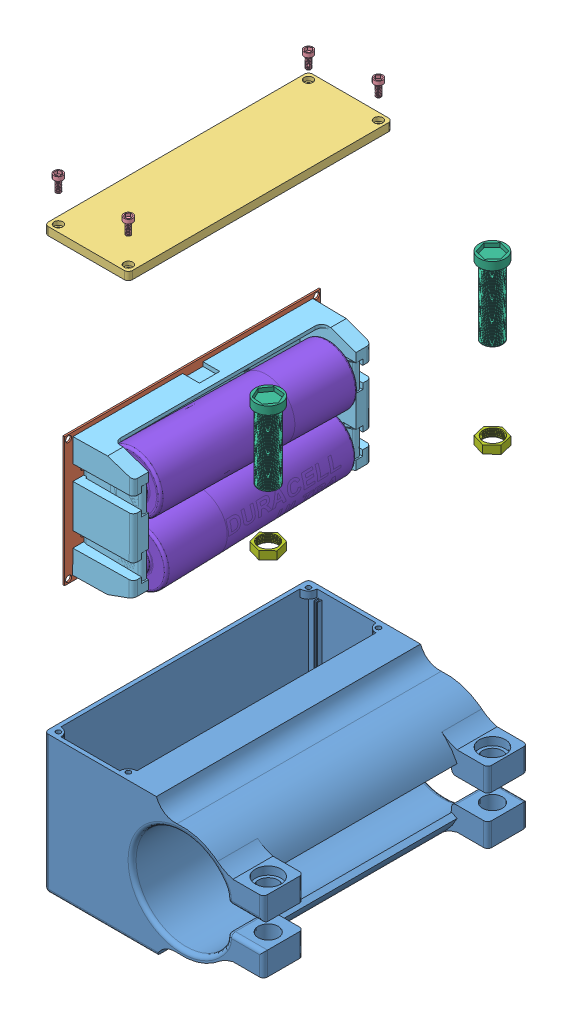
SolidWorks assembly Ensamblaje, configuration Predeterminado. Lengths in mm.
Overall size (55.54 155.38 66.01).
15 component instances, 9 part files, 19 mates.
Components (placement in the parent):
- Pieza_Delantera-1: Pieza_Delantera [Predeterminado] at (-76.9358 49.8795 33.005) size (54.77 34.5 66.01)
- PCB_Dispositivo-1: PCB_Dispositivo [Predeterminado] at (-73.2858 112.174 32.005) x (0 1 0) z (-1 0 0) size (32.26 64.01 2.93)
- Pieza_Tapadera-1: Pieza_Tapadera [Predeterminado] at (-55.9358 193.6998 -33.005) x (0 0 1) z (1 0 0) size (66.01 2 21)
- Pieza_Tornillo_Peque-1: Pieza_Tornillo_Peque [Predeterminado] at (-75.1756 204.7566 31.2449) x (-0.969898 0 -0.243511) z (-0.243511 0 0.969898) size (2.2 4.01 2.2)
- Pieza_Tornillo_Peque-2: Pieza_Tornillo_Peque [Predeterminado] at (-57.6959 204.2798 31.2449) x (0.987486 0 -0.157707) z (-0.157707 0 -0.987486) size (2.2 4.01 2.2)
- Pieza_Tornillo_Peque-3: Pieza_Tornillo_Peque [Predeterminado] at (-57.6959 202.9475 -31.2449) x (-0.365026 0 0.930997) z (0.930997 0 0.365026) size (2.2 4.01 2.2)
- Pieza_Tornillo_Peque-4: Pieza_Tornillo_Peque [Predeterminado] at (-75.1756 200.2508 -31.2449) x (0.24603 0 0.969262) z (0.969262 0 -0.24603) size (2.2 4.01 2.2)
- User Library-1013-1-1: User Library-1013-1 [Default] at (-72.8743 133.2117 -0.0275) x (0 0.001436 0.999999) z (1 0 0) size (60.04 29.98 18.93)
- Pieza_Tubo-1: Pieza_Tubo [Predeterminado] at (-42.499 66.6295 97.4394) x (0.561173 -0.827699 0) z (0.827699 0.561173 0) size (25 200 25) (hidden)
- Pieza_tornillo_grande-1: Pieza_tornillo_grande [Predeterminado] at (-25.9904 182.887 -28.005) x (0.687028 0 0.726631) z (0.726631 0 -0.687028) size (6.5 19.01 6.5)
- Pieza_tornillo_grande-2: Pieza_tornillo_grande [Predeterminado] at (-25.9904 179.6392 28.005) x (-0.78341 0 -0.621505) z (-0.621505 0 0.78341) size (6.5 19.01 6.5)
- Pieza_tuerca-1: Pieza_tuerca [Predeterminado] at (-25.9904 140.8997 -28.005) x (0.679385 0 0.733782) z (-0.733782 0 0.679385) size (5.64 2.11 6.5)
- Pieza_tuerca-2: Pieza_tuerca [Predeterminado] at (-25.9904 146.0389 28.005) x (0.970418 0 -0.241431) z (0.241431 0 0.970418) size (5.64 2.11 6.5)
- User Library-duracell ultra aa 1_5v mx 1500 lr6-1: User Library-duracell ultra aa 1_5v mx 1500 lr6 [Default] at (-63.6575 140.125 24.0992) x (0.008752 0.999959 -0.002135) z (-0.999821 0.008714 -0.016811) size (14.5 50.25 14.5)
- User Library-duracell ultra aa 1_5v mx 1500 lr6-2: User Library-duracell ultra aa 1_5v mx 1500 lr6 [Default] at (-63.6031 125.1631 -23.913) x (0.063033 0.997993 0.006079) z (0.997721 -0.062866 -0.024527) size (14.5 50.25 14.5)
Mates (geometry in assembly coordinates):
- Coincidente1: coincident anti-aligned: plane of Pieza_Delantera-1 through (-73.2858 82.0165 -31.005) normal (1 0 0); plane of PCB_Dispositivo-1 through (-73.2858 117 30.735) normal (-1 0 0)
- Coincidente2: coincident anti-aligned: plane of Pieza_Delantera-1 through (-73.2858 82.0165 31.005) normal (1 0 0); plane of PCB_Dispositivo-1 through (-73.2858 117 30.735) normal (-1 0 0)
- Coincidente3: coincident anti-aligned: plane of Pieza_Delantera-1 through (-56.9358 83.8795 32.005) normal (0 0 -1); plane of PCB_Dispositivo-1 through (-72.8743 149.258 32.005) normal (0 0 1)
- Concéntrica13: concentric anti-aligned: circle of Pieza_Tornillo_Peque-2; circle of Pieza_Delantera-1
- Concéntrica15: concentric anti-aligned: circle of Pieza_Delantera-1; circle of Pieza_Tornillo_Peque-3
- Concéntrica16: concentric anti-aligned: circle of Pieza_Delantera-1; circle of Pieza_Tornillo_Peque-4
- Coincidente21: coincident anti-aligned: plane of PCB_Dispositivo-1 through (-72.8743 117 30.735) normal (1 0 0); plane of User Library-1013-1-1 through (-72.8743 148.1605 -25.957) normal (-1 0 0)
- Concéntrica17: concentric anti-aligned: cylinder of PCB_Dispositivo-1; cylinder of User Library-1013-1-1 through (-74.4491 119.2023 -27.4328) axis (1 0 0) radius 0.635
- Tangente2: tangent aligned: cylinder of PCB_Dispositivo-1 through (-72.8743 125.9323 27.4273) axis (1 0 0) radius 0.595; plane of User Library-1013-1-1 through (-75.8715 126.527 27.1982) normal (0 0.999999 -0.001436)
- Concéntrica18: concentric anti-aligned: circle of Pieza_Delantera-1; circle of Pieza_Tapadera-1
- Concéntrica19: concentric anti-aligned: circle of Pieza_Delantera-1; circle of Pieza_Tapadera-1
- Concéntrica20: concentric anti-aligned: circle of Pieza_Delantera-1; circle of Pieza_Tapadera-1
- Concéntrica21: concentric anti-aligned: circle of Pieza_Delantera-1; circle of Pieza_Tapadera-1
- Concéntrica22: concentric anti-aligned: cylinder of Pieza_Delantera-1 through (-42.499 66.6295 33.005) axis (0 0 -1) radius 12.5; cylinder of Pieza_Tubo-1 through (-42.499 66.6295 -102.5606) axis (0 0 1) radius 12.5
- Concéntrica23: concentric anti-aligned: circle of Pieza_Delantera-1; circle of Pieza_Tornillo_Peque-1
- Concéntrica24: concentric aligned: circle of Pieza_Delantera-1; circle of Pieza_tornillo_grande-1
- Concéntrica25: concentric aligned: circle of Pieza_Delantera-1; circle of Pieza_tornillo_grande-2
- Concéntrica26: concentric aligned: circle of Pieza_Delantera-1; circle of Pieza_tuerca-1
- Concéntrica27: concentric aligned: circle of Pieza_Delantera-1; circle of Pieza_tuerca-2
